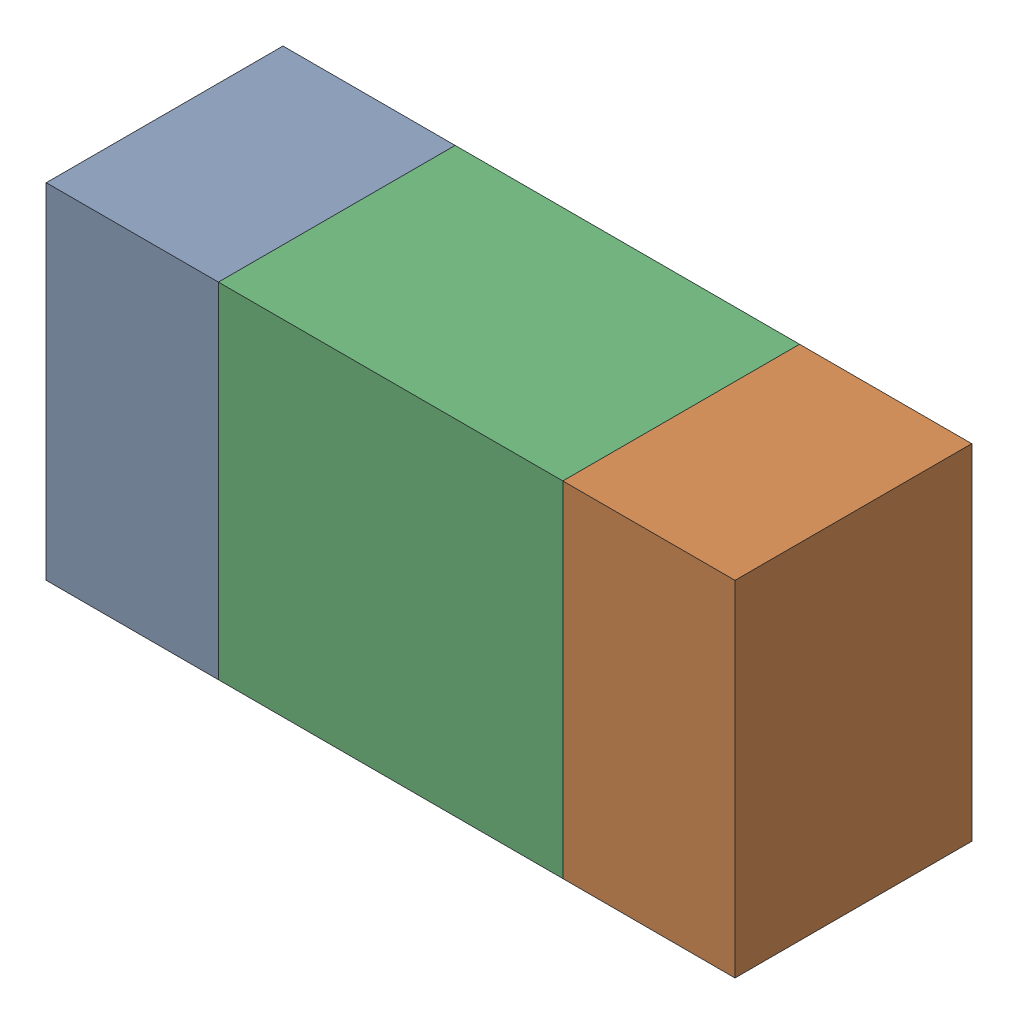
SolidWorks assembly R55, configuration ﾃﾞﾌｫﾙﾄ. Lengths in mm.
Overall size (1.6 0.8 0.55).
6 component instances, 2 part files, 0 mates.
Components (placement in the parent):
- 689261512-1: 689261512 [ﾃﾞﾌｫﾙﾄ] at (43.6001 26.0001 0) size (0.4 0.8 0.55)
  - Extruded_32-1: Extruded_32 [ﾃﾞﾌｫﾙﾄ] at origin size (0.4 0.8 0.55)
- 689261512-2: 689261512 [ﾃﾞﾌｫﾙﾄ] at (44.8001 26.0001 0) size (0.4 0.8 0.55)
  - Extruded_32-1: Extruded_32 [ﾃﾞﾌｫﾙﾄ] at origin size (0.4 0.8 0.55)
- 689261648-1: 689261648 [ﾃﾞﾌｫﾙﾄ] at (44.2 26.0001 0) size (0.8 0.8 0.55)
  - Extruded_33-1: Extruded_33 [ﾃﾞﾌｫﾙﾄ] at origin size (0.8 0.8 0.55)
